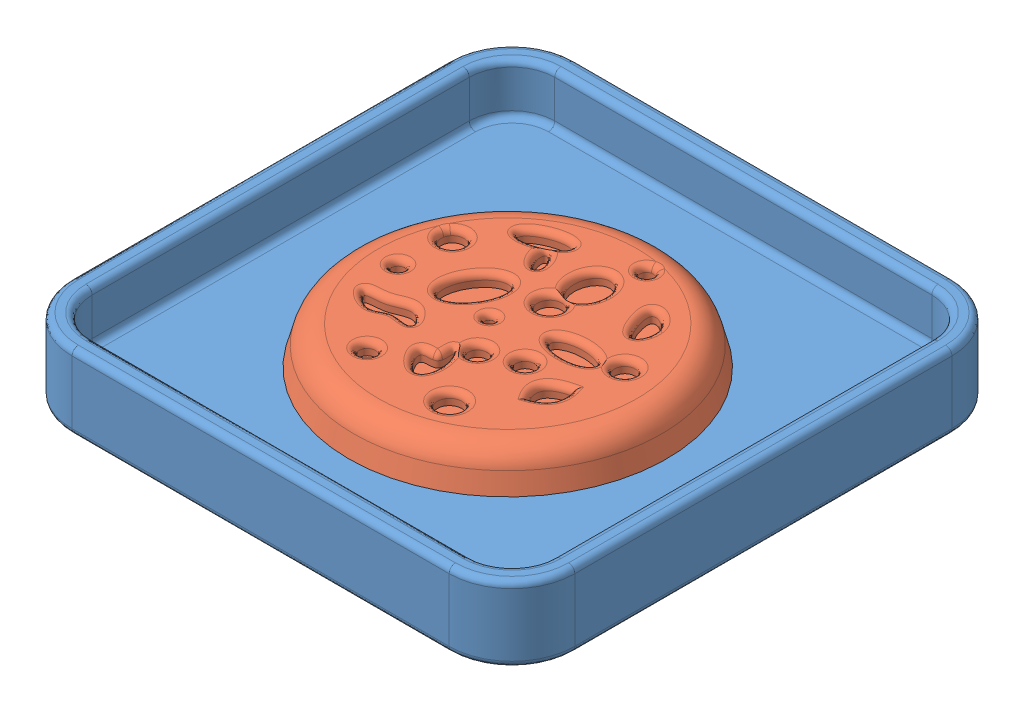
SolidWorks assembly Assem3, configuration Default. Lengths in mm.
Overall size (40 6 40).
2 component instances, 2 part files, 2 mates.
Components (placement in the parent):
- Tile-1: Tile [Default] at (12.986 16.4343 32.708) size (40 6 40)
- BarrenPlanet-1: BarrenPlanet [Default] at (12.586 18.4343 32.6469) size (35 3.13 35)
Mates (geometry in assembly coordinates):
- Coincident1: coincident anti-aligned: plane of Tile-1 through (-2.014 18.4343 47.708) normal (0 1 0); plane of BarrenPlanet-1 through (12.586 18.4343 32.6469) normal (0 -1 0)
- Coincident2: coincident aligned: line of Tile-1 through (-4.914 18.4343 17.708) axis (0 0 1); line of BarrenPlanet-1 through (-4.914 18.4343 15.1469) axis (0 0 1)
